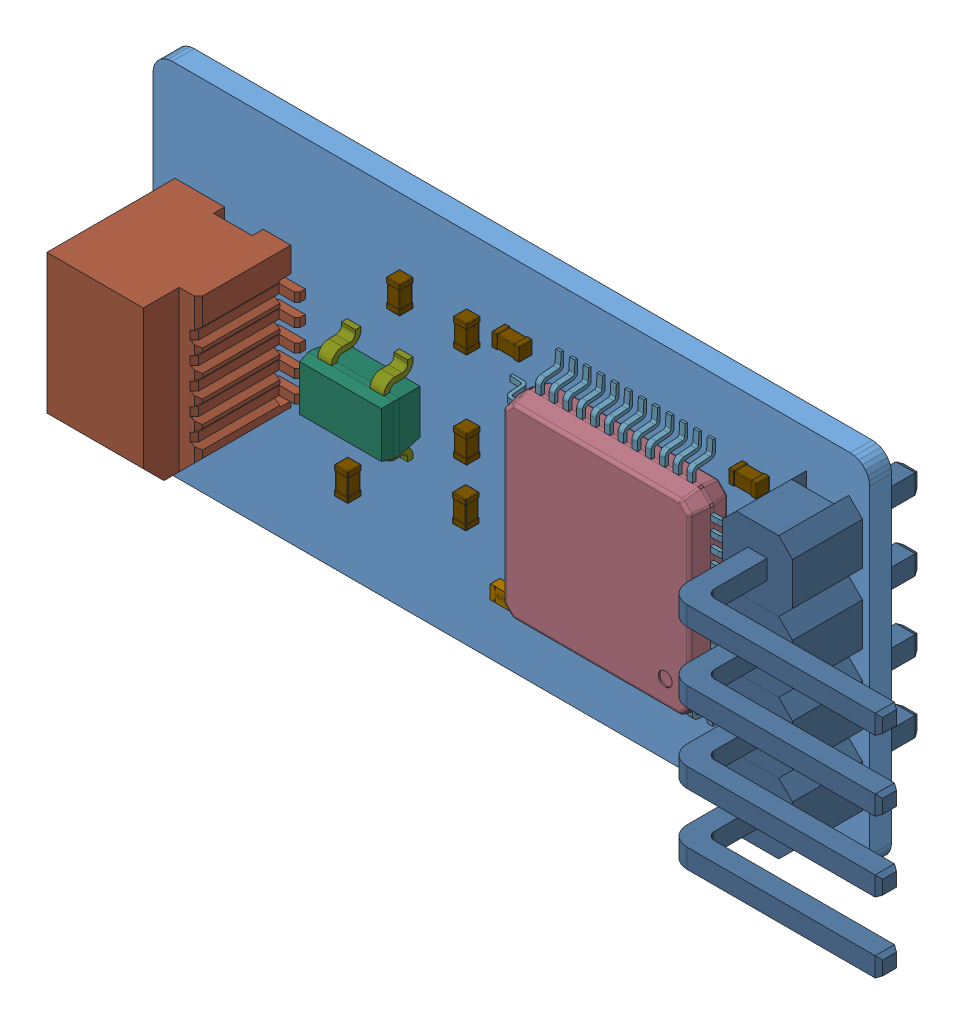
SolidWorks assembly Плата контроллера, configuration По умолчанию. Lengths in mm.
Overall size (31.83 13 8.45).
99 component instances, 18 part files, 0 mates.
Components (placement in the parent):
- Board-1: Board [По умолчанию] at origin size (26 13 0.8)
- C2-1: C2 [По умолчанию] at origin size (3.2 2.5 1.7)
  - SMD_1210-1: SMD_1210 [По умолчанию] at (3.1001 6.0999 -1.5984) x (0 -1 0) z (0 0 -1) size (2.5 3.2 1.7)
- VD1-1: VD1 [По умолчанию] at origin size (0.9 1.7 0.9)
  - User_Library-LTST-C190GKT-1: User_Library-LTST-C190GKT [По умолчанию] at (19.5 10.725 -0.7984) x (1 0 0) z (0 0 -1) size (0.9 1.7 0.9)
    - Pad005-1: Pad005 [По умолчанию] at origin size (0.35 0.15 0.31)
    - Pad001-1: Pad001 [По умолчанию] at origin size (0.9 1.7 0.01)
    - Pad004-1: Pad004 [По умолчанию] at origin size (0.35 0.15 0.31)
    - Pad003-1: Pad003 [По умолчанию] at origin size (0.8 1.7 0.02)
    - Lens-1: Lens [По умолчанию] at origin size (0.9 1.15 0.6)
    - Pad-1: Pad [По умолчанию] at origin size (0.9 1.7 0.28)
- R1-1: R1 [По умолчанию] at origin size (1 0.5 0.35)
  - User_Library-R_0402-1: User_Library-R_0402 [По умолчанию] at (17.2749 11.6501 -0.7984) x (1 0 0) z (0 0 -1) size (1 0.5 0.35)
- X2-1: X2 [По умолчанию] at origin size (8.62 10.16 8.45)
  - User_Library-PLS-4R_gold-1: User_Library-PLS-4R_gold [По умолчанию] at (24.4751 2.75 0) x (1 0 0) z (0 -1 0) size (8.62 8.45 10.16)
- X1-1: X1 [По умолчанию] at origin size (5.1 5.8 4.7)
  - 533091070-1: 533091070 [По умолчанию] at (2.9251 6.4999 2.35) x (0 -1 0) z (-1 0 0) size (5.8 4.7 5.1)
    - Open CASCADE STEP translator 6.8 2.6.1.1-1: Open CASCADE STEP translator 6.8 2.6.1.1 [По умолчанию] at origin size (5.8 4.7 5.1)
- R3-1: R3 [По умолчанию] at origin size (1 0.5 0.35)
  - User_Library-R_0402-1: User_Library-R_0402 [По умолчанию] at (17.3501 9.7999 -0.7984) x (-1 0 0) z (0 0 -1) size (1 0.5 0.35)
- R2-1: R2 [По умолчанию] at origin size (1 0.5 0.35)
  - User_Library-R_0402-1: User_Library-R_0402 [По умолчанию] at (13.0849 2.4499 0) x (1 0 0) z (0 0 1) size (1 0.5 0.35)
- G1-1: G1 [По умолчанию] at origin size (7 5.08 1.3)
  - User_Library-KXO-97V-1: User_Library-KXO-97V [По умолчанию] at (15.9249 4.5001 -0.7984) x (-1 0 0) z (0 0 -1) size (7 5.08 1.3)
- DD1-1: DD1 [По умолчанию] at origin size (9.02 9.02 1.53)
  - vbh48a-1: vbh48a [По умолчанию] at (17.5501 6.5001 0.7) x (1 0 0) z (0 -1 0) size (9.02 1.53 9.02)
    - BODY_VBH48A-1: BODY_VBH48A [По умолчанию] at (0 0.125 0) x (0 0 -1) z (1 0 0) size (7.01 1.46 7.01)
    - LEAD_VBH48A-1: LEAD_VBH48A [По умолчанию] at (-2.75 -0.4875 3.9) size (0.2 0.86 1.01)
    - LEAD_VBH48A-2: LEAD_VBH48A [По умолчанию] at (-2.25 -0.4875 3.9) size (0.2 0.86 1.01)
    - LEAD_VBH48A-3: LEAD_VBH48A [По умолчанию] at (-1.75 -0.4875 3.9) size (0.2 0.86 1.01)
    - LEAD_VBH48A-4: LEAD_VBH48A [По умолчанию] at (-1.25 -0.4875 3.9) size (0.2 0.86 1.01)
    - LEAD_VBH48A-5: LEAD_VBH48A [По умолчанию] at (-0.75 -0.4875 3.9) size (0.2 0.86 1.01)
    - LEAD_VBH48A-6: LEAD_VBH48A [По умолчанию] at (-0.25 -0.4875 3.9) size (0.2 0.86 1.01)
    - LEAD_VBH48A-7: LEAD_VBH48A [По умолчанию] at (0.25 -0.4875 3.9) size (0.2 0.86 1.01)
    - LEAD_VBH48A-8: LEAD_VBH48A [По умолчанию] at (0.75 -0.4875 3.9) size (0.2 0.86 1.01)
    - LEAD_VBH48A-9: LEAD_VBH48A [По умолчанию] at (1.25 -0.4875 3.9) size (0.2 0.86 1.01)
    - LEAD_VBH48A-10: LEAD_VBH48A [По умолчанию] at (1.75 -0.4875 3.9) size (0.2 0.86 1.01)
    - LEAD_VBH48A-11: LEAD_VBH48A [По умолчанию] at (2.25 -0.4875 3.9) size (0.2 0.86 1.01)
    - LEAD_VBH48A-12: LEAD_VBH48A [По умолчанию] at (2.75 -0.4875 3.9) size (0.2 0.86 1.01)
    - LEAD_VBH48A-13: LEAD_VBH48A [По умолчанию] at (3.9 -0.4875 2.75) x (0 0 -1) z (1 0 0) size (0.2 0.86 1.01)
    - LEAD_VBH48A-14: LEAD_VBH48A [По умолчанию] at (3.9 -0.4875 2.25) x (0 0 -1) z (1 0 0) size (0.2 0.86 1.01)
    - LEAD_VBH48A-15: LEAD_VBH48A [По умолчанию] at (3.9 -0.4875 1.75) x (0 0 -1) z (1 0 0) size (0.2 0.86 1.01)
    - LEAD_VBH48A-16: LEAD_VBH48A [По умолчанию] at (3.9 -0.4875 1.25) x (0 0 -1) z (1 0 0) size (0.2 0.86 1.01)
    - LEAD_VBH48A-17: LEAD_VBH48A [По умолчанию] at (3.9 -0.4875 0.75) x (0 0 -1) z (1 0 0) size (0.2 0.86 1.01)
    - LEAD_VBH48A-18: LEAD_VBH48A [По умолчанию] at (3.9 -0.4875 0.25) x (0 0 -1) z (1 0 0) size (0.2 0.86 1.01)
    - LEAD_VBH48A-19: LEAD_VBH48A [По умолчанию] at (3.9 -0.4875 -0.25) x (0 0 -1) z (1 0 0) size (0.2 0.86 1.01)
    - LEAD_VBH48A-20: LEAD_VBH48A [По умолчанию] at (3.9 -0.4875 -0.75) x (0 0 -1) z (1 0 0) size (0.2 0.86 1.01)
    - LEAD_VBH48A-21: LEAD_VBH48A [По умолчанию] at (3.9 -0.4875 -1.25) x (0 0 -1) z (1 0 0) size (0.2 0.86 1.01)
    - LEAD_VBH48A-22: LEAD_VBH48A [По умолчанию] at (3.9 -0.4875 -1.75) x (0 0 -1) z (1 0 0) size (0.2 0.86 1.01)
    - LEAD_VBH48A-23: LEAD_VBH48A [По умолчанию] at (3.9 -0.4875 -2.25) x (0 0 -1) z (1 0 0) size (0.2 0.86 1.01)
    - LEAD_VBH48A-24: LEAD_VBH48A [По умолчанию] at (3.9 -0.4875 -2.75) x (0 0 -1) z (1 0 0) size (0.2 0.86 1.01)
    - LEAD_VBH48A-25: LEAD_VBH48A [По умолчанию] at (2.75 -0.4875 -3.9) x (-1 0 0) z (0 0 -1) size (0.2 0.86 1.01)
    - LEAD_VBH48A-26: LEAD_VBH48A [По умолчанию] at (2.25 -0.4875 -3.9) x (-1 0 0) z (0 0 -1) size (0.2 0.86 1.01)
    - LEAD_VBH48A-27: LEAD_VBH48A [По умолчанию] at (1.75 -0.4875 -3.9) x (-1 0 0) z (0 0 -1) size (0.2 0.86 1.01)
    - LEAD_VBH48A-28: LEAD_VBH48A [По умолчанию] at (1.25 -0.4875 -3.9) x (-1 0 0) z (0 0 -1) size (0.2 0.86 1.01)
    - LEAD_VBH48A-29: LEAD_VBH48A [По умолчанию] at (0.75 -0.4875 -3.9) x (-1 0 0) z (0 0 -1) size (0.2 0.86 1.01)
    - LEAD_VBH48A-30: LEAD_VBH48A [По умолчанию] at (0.25 -0.4875 -3.9) x (-1 0 0) z (0 0 -1) size (0.2 0.86 1.01)
    - LEAD_VBH48A-31: LEAD_VBH48A [По умолчанию] at (-0.25 -0.4875 -3.9) x (-1 0 0) z (0 0 -1) size (0.2 0.86 1.01)
    - LEAD_VBH48A-32: LEAD_VBH48A [По умолчанию] at (-0.75 -0.4875 -3.9) x (-1 0 0) z (0 0 -1) size (0.2 0.86 1.01)
    - LEAD_VBH48A-33: LEAD_VBH48A [По умолчанию] at (-1.25 -0.4875 -3.9) x (-1 0 0) z (0 0 -1) size (0.2 0.86 1.01)
    - LEAD_VBH48A-34: LEAD_VBH48A [По умолчанию] at (-1.75 -0.4875 -3.9) x (-1 0 0) z (0 0 -1) size (0.2 0.86 1.01)
    - LEAD_VBH48A-35: LEAD_VBH48A [По умолчанию] at (-2.25 -0.4875 -3.9) x (-1 0 0) z (0 0 -1) size (0.2 0.86 1.01)
    - LEAD_VBH48A-36: LEAD_VBH48A [По умолчанию] at (-2.75 -0.4875 -3.9) x (-1 0 0) z (0 0 -1) size (0.2 0.86 1.01)
    - LEAD_VBH48A-37: LEAD_VBH48A [По умолчанию] at (-3.9 -0.4875 -2.75) x (0 0 1) z (-1 0 0) size (0.2 0.86 1.01)
    - LEAD_VBH48A-38: LEAD_VBH48A [По умолчанию] at (-3.9 -0.4875 -2.25) x (0 0 1) z (-1 0 0) size (0.2 0.86 1.01)
    - LEAD_VBH48A-39: LEAD_VBH48A [По умолчанию] at (-3.9 -0.4875 -1.75) x (0 0 1) z (-1 0 0) size (0.2 0.86 1.01)
    - LEAD_VBH48A-40: LEAD_VBH48A [По умолчанию] at (-3.9 -0.4875 -1.25) x (0 0 1) z (-1 0 0) size (0.2 0.86 1.01)
    - LEAD_VBH48A-41: LEAD_VBH48A [По умолчанию] at (-3.9 -0.4875 -0.75) x (0 0 1) z (-1 0 0) size (0.2 0.86 1.01)
    - LEAD_VBH48A-42: LEAD_VBH48A [По умолчанию] at (-3.9 -0.4875 -0.25) x (0 0 1) z (-1 0 0) size (0.2 0.86 1.01)
    - LEAD_VBH48A-43: LEAD_VBH48A [По умолчанию] at (-3.9 -0.4875 0.25) x (0 0 1) z (-1 0 0) size (0.2 0.86 1.01)
    - LEAD_VBH48A-44: LEAD_VBH48A [По умолчанию] at (-3.9 -0.4875 0.75) x (0 0 1) z (-1 0 0) size (0.2 0.86 1.01)
    - LEAD_VBH48A-45: LEAD_VBH48A [По умолчанию] at (-3.9 -0.4875 1.25) x (0 0 1) z (-1 0 0) size (0.2 0.86 1.01)
    - LEAD_VBH48A-46: LEAD_VBH48A [По умолчанию] at (-3.9 -0.4875 1.75) x (0 0 1) z (-1 0 0) size (0.2 0.86 1.01)
    - LEAD_VBH48A-47: LEAD_VBH48A [По умолчанию] at (-3.9 -0.4875 2.25) x (0 0 1) z (-1 0 0) size (0.2 0.86 1.01)
    - LEAD_VBH48A-48: LEAD_VBH48A [По умолчанию] at (-3.9 -0.4875 2.75) x (0 0 1) z (-1 0 0) size (0.2 0.86 1.01)
- DA1-1: DA1 [По умолчанию] at origin size (3.1 3.2 1.44)
  - User_Library-SOT23-5-3-1: User_Library-SOT23-5-3 [По умолчанию] at (7.3049 4.8999 0) x (1 0 0) z (0 0 1) size (3.1 3.2 1.44)
    - User_Library-SOT23-5-3_Free-Models003-1: User_Library-SOT23-5-3_Free-Models003 [По умолчанию] at origin size (3.1 1.8 1.44)
    - User_Library-SOT23-5-3_Fusion-1: User_Library-SOT23-5-3_Fusion [По умолчанию] at origin size (2.4 3.2 1.07)
- C11-1: C11 [По умолчанию] at origin size (0.8 1.6 0.9)
  - CAPC0603-1: CAPC0603 [По умолчанию] at (21.0901 4.5001 -0.7984) x (0 1 0) z (-1 0 0) size (1.6 0.9 0.8)
- C10-1: C10 [По умолчанию] at origin size (0.51 1 0.51)
  - User_Library-C0402-1-1: User_Library-C0402-1 [По умолчанию] at (21.0541 7.2421 -1.0334) x (0 -1 0) z (0 0 -1) size (1 0.51 0.51)
- C9-1: C9 [По умолчанию] at origin size (1 0.51 0.51)
  - User_Library-C0402-1-1: User_Library-C0402-1 [По умолчанию] at (13.2629 10.2959 0.235) x (1 0 0) z (0 0 1) size (1 0.51 0.51)
- C8-1: C8 [По умолчанию] at origin size (1 0.51 0.51)
  - User_Library-C0402-1-1: User_Library-C0402-1 [По умолчанию] at (21.8671 10.8041 0.235) x (-1 0 0) z (0 0 1) size (1 0.51 0.51)
- C7-1: C7 [По умолчанию] at origin size (1 0.51 0.51)
  - User_Library-C0402-1-1: User_Library-C0402-1 [По умолчанию] at (21.8671 2.6541 0.235) x (-1 0 0) z (0 0 1) size (1 0.51 0.51)
- C6-1: C6 [По умолчанию] at origin size (0.51 1 0.51)
  - User_Library-C0402-1-1: User_Library-C0402-1 [По умолчанию] at (11.8341 4.5329 0.235) x (0 1 0) z (0 0 1) size (1 0.51 0.51)
- C5-1: C5 [По умолчанию] at origin size (0.51 1 0.51)
  - User_Library-C0402-1-1: User_Library-C0402-1 [По умолчанию] at (11.3659 6.6171 0.235) x (0 -1 0) z (0 0 1) size (1 0.51 0.51)
- C4-1: C4 [По умолчанию] at origin size (0.51 1 0.51)
  - User_Library-C0402-1-1: User_Library-C0402-1 [По умолчанию] at (11.3659 10.0721 0.235) x (0 -1 0) z (0 0 1) size (1 0.51 0.51)
- C3-1: C3 [По умолчанию] at origin size (0.51 1 0.51)
  - User_Library-C0402-1-1: User_Library-C0402-1 [По умолчанию] at (7.5541 3.2564 0.235) x (0 1 0) z (0 0 1) size (1 0.51 0.51)
- C1-1: C1 [По умолчанию] at origin size (0.51 1 0.51)
  - User_Library-C0402-1-1: User_Library-C0402-1 [По умолчанию] at (9.4341 10.0879 0.235) x (0 1 0) z (0 0 1) size (1 0.51 0.51)
